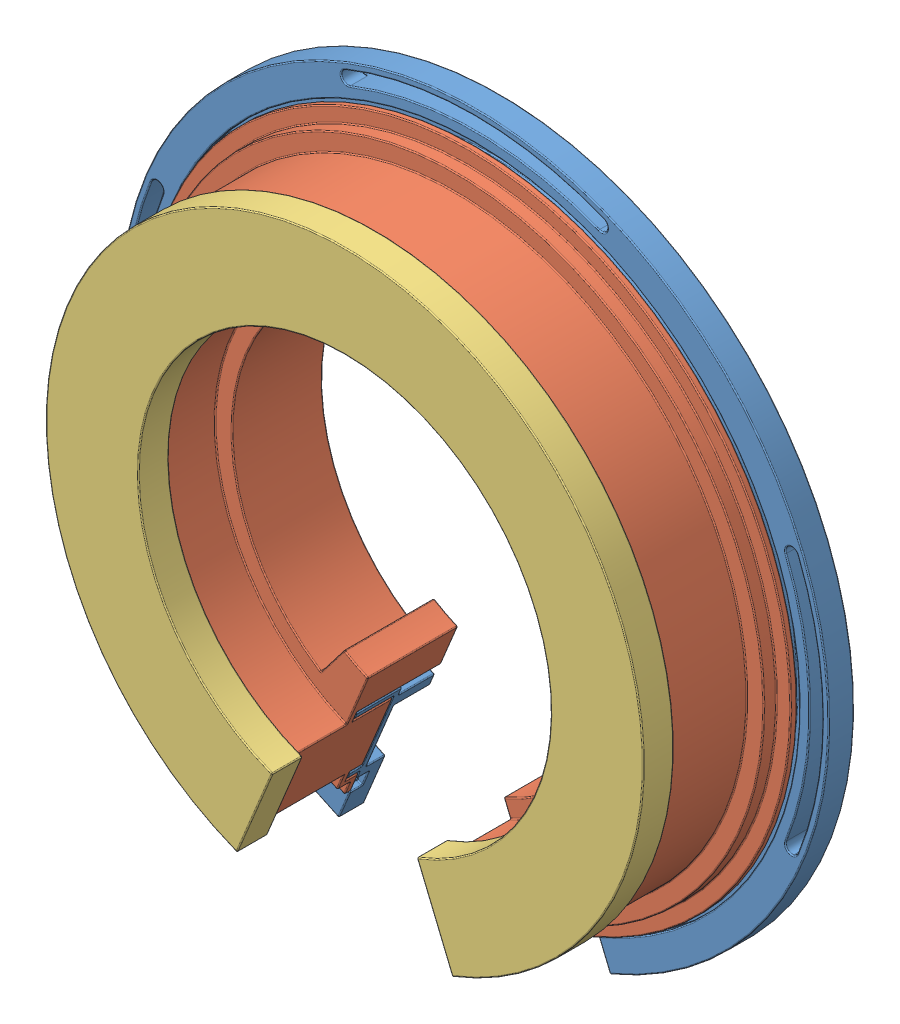
SolidWorks assembly Case Montada, configuration Valor predeterminado. Lengths in mm.
Overall size (167.75 161.29 41.2).
3 component instances, 3 part files, 6 mates.
Components (placement in the parent):
- CD-Fixo Inferior-1: CD-Fixo Inferior [Valor predeterminado] at (-7.6296 -10.4244 160.0833) size (167.75 161.29 19.33)
- CD-Movel-1: CD-Movel [Valor predeterminado] at (-7.6296 -10.4244 159.5833) size (152.75 146.86 40)
- CD-Tampa-1: CD-Tampa [Valor predeterminado] at (-7.6296 -10.4244 159.0833) size (141.4 136.58 7.2)
Mates (geometry in assembly coordinates):
- Concêntrico1: concentric anti-aligned: cylinder of CD-Movel-1 through (-7.6296 -10.4244 196.0833) axis (0 0 -1) radius 50.5; cylinder of CD-Fixo Inferior-1 through (-7.6296 -10.4244 166.5833) axis (0 0 1) radius 48.5
- Coincidente1: coincident anti-aligned: plane of CD-Movel-1 through (-7.6296 -10.4244 168.0833) normal (0 0 -1); plane of CD-Fixo Inferior-1 through (-7.6296 -10.4244 168.0833) normal (0 0 1)
- ÂnguloLimite2: limit planar angle = 0 rad anti-aligned: plane of CD-Movel-1 through (-5.7818 -9.659 157.5833) normal (-0.92388 -0.382683 0); plane of CD-Fixo Inferior-1 through (21.3034 -76.3553 168.0833) normal (0.92388 0.382683 0)
- Concêntrico2: concentric aligned: cylinder of CD-Tampa-1 through (-7.6296 -10.4244 198.7833) axis (0 0 -1) radius 70.7; cylinder of CD-Movel-1 through (-7.6296 -10.4244 196.0833) axis (0 0 -1) radius 69
- Paralelo3: parallel aligned: plane of CD-Tampa-1 through (-33.1069 -76.3744 198.7833) normal (0.92388 -0.382683 0); plane of CD-Movel-1 through (-7.6296 -10.4244 383.5334) normal (0.92388 -0.382683 0)
- Coincidente5: coincident anti-aligned: plane of CD-Tampa-1 through (-7.6296 -10.4244 197.5833) normal (0 0 -1); plane of CD-Movel-1 through (-7.6296 -10.4244 197.5833) normal (0 0 1)
